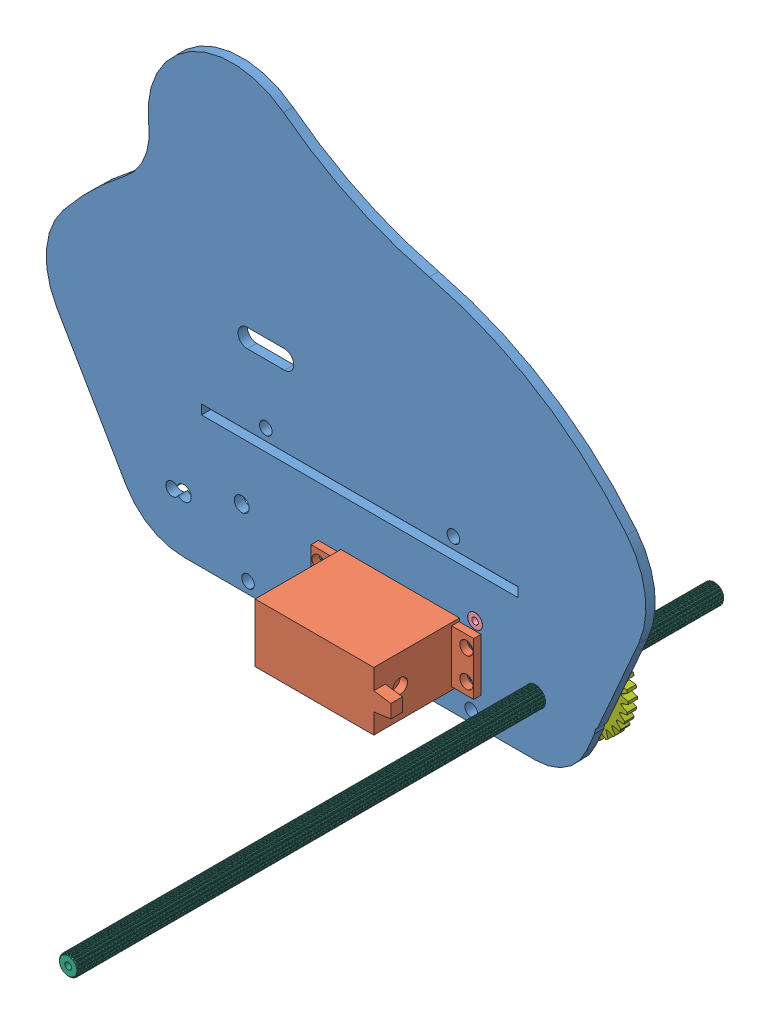
SolidWorks assembly Flipper Drive, configuration Default. Lengths in mm.
Overall size (204.7 154.42 220.73).
8 component instances, 8 part files, 14 mates.
Components (placement in the parent):
- drive plate_in-flipper-1: drive plate_in-flipper [Default] at origin size (204.7 154.42 3.2)
- Servo_ContRotation-1: Servo_ContRotation [Default] at (53.432 8.9078 5.7004) x (0 1 0) z (0 0 -1) size (20 55.5 42.8)
- 12T Gear_Futaba Spline-1: 12T Gear_Futaba Spline [Default] at (83.532 18.9078 -7.3013) x (-0.874398 0.485209 0) z (0 0 -1) size (13.64 13.64 3.2)
- 3x_Custom Axle w-ends-1: 3x_Custom Axle w-ends [Default] at (99.4008 30.8094 -8.1661) size (6.65 6.65 22.73)
- 14T Gear_Custom Axle-1: 14T Gear_Custom Axle [Default] at (99.4008 30.8094 -12.1019) size (15.87 15.66 3.2)
- 28x_Custom Axle-no ends-1: 28x_Custom Axle-no ends [Default] at (120.015 18.9078 52.324) x (-0.313685 -0.949527 0) z (0 0 1) size (6.65 6.65 220.73)
- 34T Gear_Custom Axle-1: 34T Gear_Custom Axle [Default] at (120.015 18.9078 -12.1019) size (35.7 35.63 3.2)
- 28T Gear_Custom Axle-1: 28T Gear_Custom Axle [Default] at (99.4008 30.8094 -8.9015) x (-0.993493 0.113896 0) z (0 0 -1) size (29.66 29.66 3.2)
Mates (geometry in assembly coordinates):
- Coincident1: coincident: plane of drive plate_in-flipper-1 through (55.081 4.5491 3.2004) normal (0 0 1); plane of Servo_ContRotation-1 through (53.432 8.9078 3.2004) normal (0 0 -1)
- Concentric5: concentric: cylinder of drive plate_in-flipper-1 through (120.015 18.9078 3.2004) axis (0 0 -1) radius 3.429; circle of 28x_Custom Axle-no ends-1
- Concentric9: concentric: cylinder of drive plate_in-flipper-1 through (48.432 23.9078 3.2004) axis (0 0 -1) radius 1.7272; cylinder of Servo_ContRotation-1 through (48.432 23.9078 3.2004) axis (0 0 1) radius 2.25
- Distance1: distance = 58.039 mm: plane of drive plate_in-flipper-1 through (55.081 4.5491 0) normal (0 0 -1); plane of 28x_Custom Axle-no ends-1 through (122.9945 18.0361 -58.039) normal (0 0 -1)
- Coincident8: coincident: plane of Servo_ContRotation-1 through (83.532 18.9078 -10.5017) normal (0 0 -1); plane of 12T Gear_Futaba Spline-1 through (83.532 18.9078 -10.5017) normal (0 0 -1)
- Concentric10: concentric: cylinder of Servo_ContRotation-1 through (83.532 18.9078 -10.5017) axis (0 0 1) radius 2.794; circle of 12T Gear_Futaba Spline-1
- Concentric11: concentric: cylinder of drive plate_in-flipper-1 through (99.4008 30.8094 3.2004) axis (0 0 -1) radius 2.54; cylinder of 3x_Custom Axle w-ends-1 through (99.4008 30.8094 3.2004) axis (0 0 -1) radius 2.5019
- Coincident9: coincident: plane of drive plate_in-flipper-1 through (55.081 4.5491 3.2004) normal (0 0 1); plane of 3x_Custom Axle w-ends-1 through (99.4008 30.8094 3.2004) normal (0 0 1)
- Concentric12: concentric: cylinder of 3x_Custom Axle w-ends-1 through (99.4008 30.8094 3.2004) axis (0 0 -1) radius 2.5019; circle of 14T Gear_Custom Axle-1
- Concentric13: concentric: circle of 28x_Custom Axle-no ends-1; circle of 34T Gear_Custom Axle-1
- Coincident10: coincident: plane of 14T Gear_Custom Axle-1 through (99.4008 30.8094 -13.7021) normal (0 0 -1); plane of 34T Gear_Custom Axle-1 through (120.015 18.9078 -13.7021) normal (0 0 -1)
- Coincident12: coincident: plane of 12T Gear_Futaba Spline-1 through (83.532 18.9078 -10.5017) normal (0 0 -1); plane of 28T Gear_Custom Axle-1 through (99.4008 30.8094 -10.5017) normal (0 0 -1)
- Concentric14: concentric: cylinder of 3x_Custom Axle w-ends-1 through (99.4008 30.8094 3.2004) axis (0 0 -1) radius 2.5019; circle of 28T Gear_Custom Axle-1
- Coincident13: coincident: plane of 14T Gear_Custom Axle-1 through (99.4008 30.8094 -10.5017) normal (0 0 1); plane of 28T Gear_Custom Axle-1 through (99.4008 30.8094 -10.5017) normal (0 0 -1)
